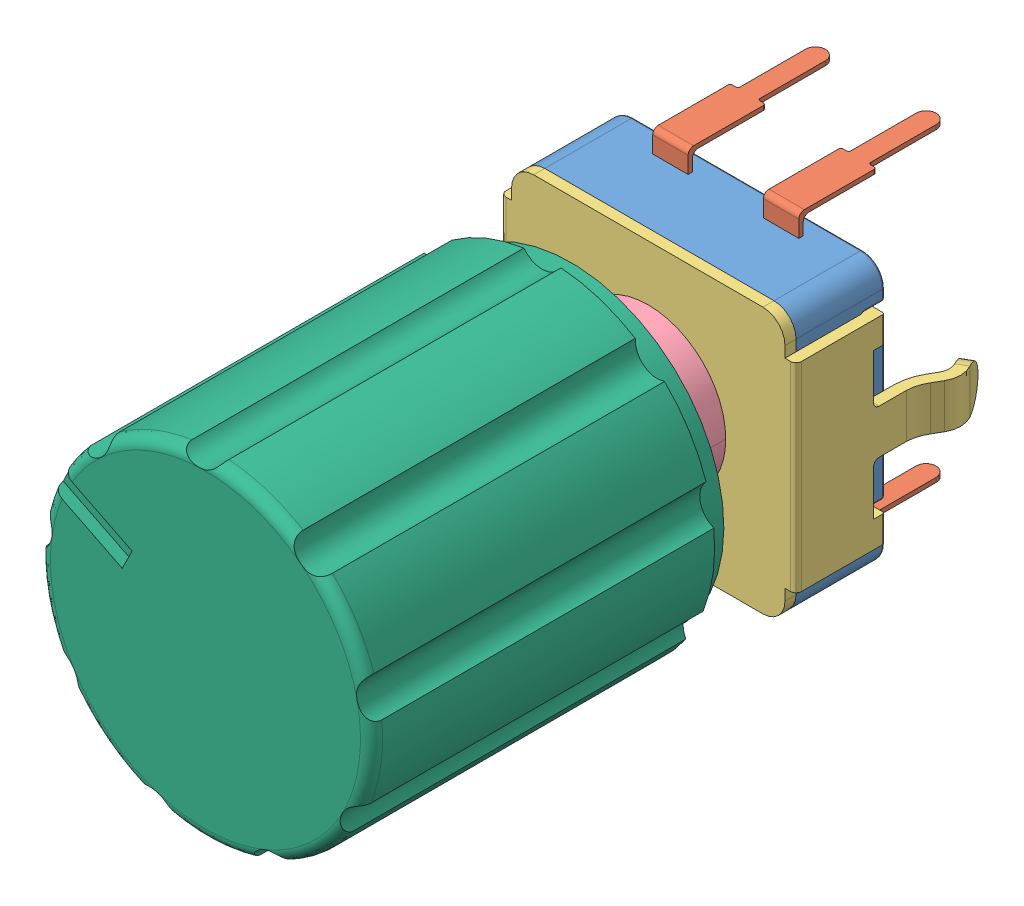
SolidWorks assembly RotaryEncoder, configuration Default. Lengths in mm.
Overall size (20.19 20.21 30.57).
12 component instances, 6 part files, 5 mates.
Components (placement in the parent):
- 12mm Incremental Encoder - BOURNS PEC11S - No Knob.STEP-1: 12mm Incremental Encoder - BOURNS PEC11S - No Knob.STEP [Default] at (-3.5981 4.986 0) size (14.62 14 30)
  - 12mm Incremental Encoder - BOURNS PEC11S.stp.STEP-1: 12mm Incremental Encoder - BOURNS PEC11S.stp.STEP [Default] at origin size (14.62 14 30)
    - 12mm Incremental Encoder Base.stp.STEP-1: 12mm Incremental Encoder Base.stp.STEP [Default] at (-3.0769 1.014 0) size (12.35 12 4)
    - 12mm Incremental Encoder Pin.stp.STEP-1: 12mm Incremental Encoder Pin.stp.STEP [Default] at (-3.0769 -4.986 0.8) x (0 -1 0) z (-1 0 0) size (1 7 1.6)
    - 12mm Incremental Encoder Pin.stp.STEP-2: 12mm Incremental Encoder Pin.stp.STEP [Default] at (-0.5769 7.014 0.8) x (0 1 0) z (1 0 0) size (1 7 1.6)
    - 12mm Incremental Encoder Pin.stp.STEP-3: 12mm Incremental Encoder Pin.stp.STEP [Default] at (-5.5769 7.014 0.8) x (0 1 0) z (1 0 0) size (1 7 1.6)
    - 12mm Incremental Encoder Pin.stp.STEP-4: 12mm Incremental Encoder Pin.stp.STEP [Default] at (-5.5769 -4.986 0.8) x (0 -1 0) z (-1 0 0) size (1 7 1.6)
    - 12mm Incremental Encoder Pin.stp.STEP-5: 12mm Incremental Encoder Pin.stp.STEP [Default] at (-0.5769 -4.986 0.8) x (0 -1 0) z (-1 0 0) size (1 7 1.6)
    - 12mm Incremental Encoder Anti-Rotation Plate.stp.STEP-1: 12mm Incremental Encoder Anti-Rotation Plate.stp.STEP [Default] at (-3.0769 1.014 4) size (14.62 12 8.24)
    - 12mm Incremental Encoder Threaded Tube.stp.STEP-1: 12mm Incremental Encoder Threaded Tube.stp.STEP [Default] at (3.3481 1.014 4.5) size (7 7 7)
    - 12mm Incremental Encoder Shaft.stp.STEP-1: 12mm Incremental Encoder Shaft.stp.STEP [Default] at (-3.0769 1.014 11.5) size (6 6 17.5)
- Knob-1: Knob [Default] at (-6.675 6 8) x (0.894996 -0.446075 0) z (-0.446075 -0.894996 0) size (15.04 16.57 15.09)
Mates (geometry in assembly coordinates):
- Concentric1: concentric: cylinder of 12mm Incremental Encoder - BOURNS PEC11S - No Knob.STEP-1/12mm Incremental Encoder - BOURNS PEC11S.stp.STEP-1/12mm Incremental Encoder Shaft.stp.STEP-1 through (-6.675 6 12) axis (0 0 1) radius 3; cylinder of Knob-1 through (-6.675 6 12) axis (0 0 -1) radius 2.7504
- Distance1: distance = 24.5 mm anti-aligned: plane of Knob-1 through (-6.675 6 24.5) normal (0 0 1); plane of 12mm Incremental Encoder - BOURNS PEC11S - No Knob.STEP-1/12mm Incremental Encoder - BOURNS PEC11S.stp.STEP-1/12mm Incremental Encoder Base.stp.STEP-1 through (-6.675 6 0) normal (0 0 -1)
- Coincident2: coincident anti-aligned: plane of 12mm Incremental Encoder - BOURNS PEC11S - No Knob.STEP-1/12mm Incremental Encoder - BOURNS PEC11S.stp.STEP-1/12mm Incremental Encoder Base.stp.STEP-1 through (-6.675 6 0) normal (0 0 -1)
- Coincident6: coincident anti-aligned: plane of 12mm Incremental Encoder - BOURNS PEC11S - No Knob.STEP-1/12mm Incremental Encoder - BOURNS PEC11S.stp.STEP-1/12mm Incremental Encoder Base.stp.STEP-1 through (-1.5 0 0) normal (0 -1 0)
- Coincident7: coincident aligned: plane of 12mm Incremental Encoder - BOURNS PEC11S - No Knob.STEP-1/12mm Incremental Encoder - BOURNS PEC11S.stp.STEP-1/12mm Incremental Encoder Anti-Rotation Plate.stp.STEP-1 through (0 10.5 4) normal (1 0 0)
